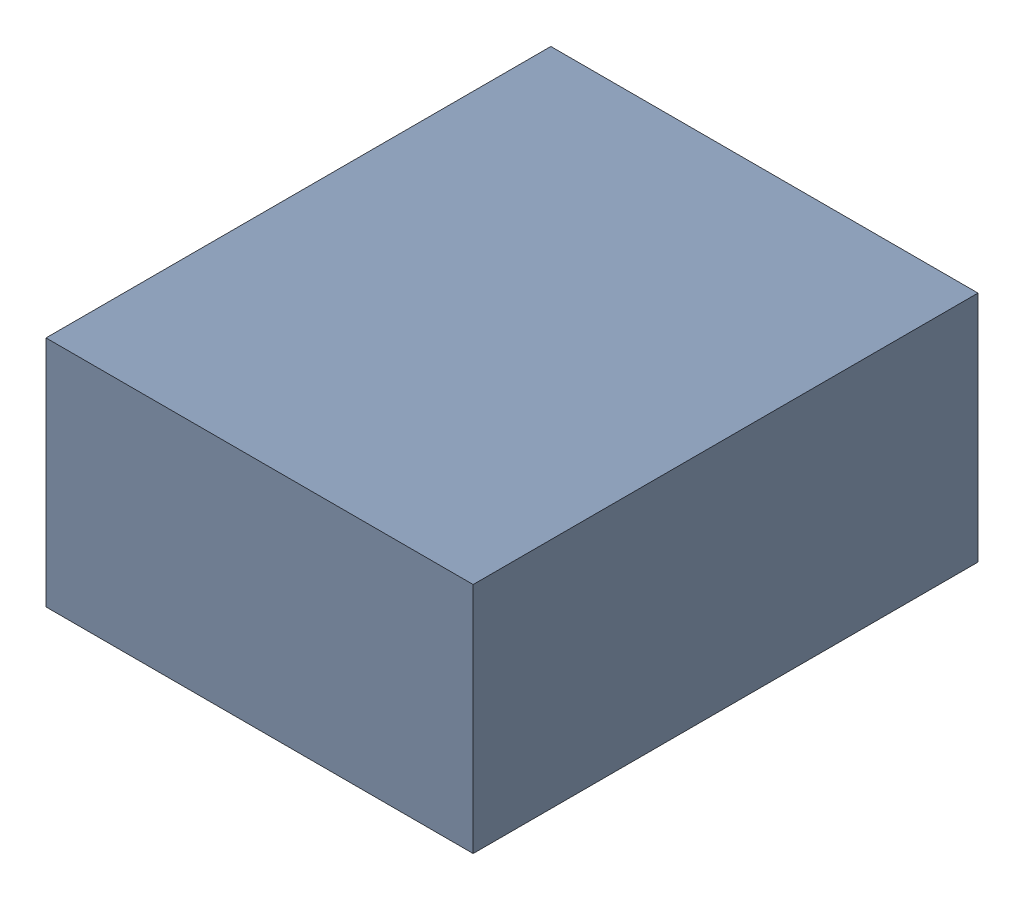
SolidWorks assembly C3, configuration Standard. Lengths in mm.
Overall size (1.1 0.6 1.3).
2 component instances, 1 part files, 0 mates.
Components (placement in the parent):
- 885542240-1: 885542240 [Standard] at (-2.9 -11.95 0) size (1.1 0.6 1.3)
  - Extruded_28-1: Extruded_28 [Standard] at origin size (1.1 0.6 1.3)
